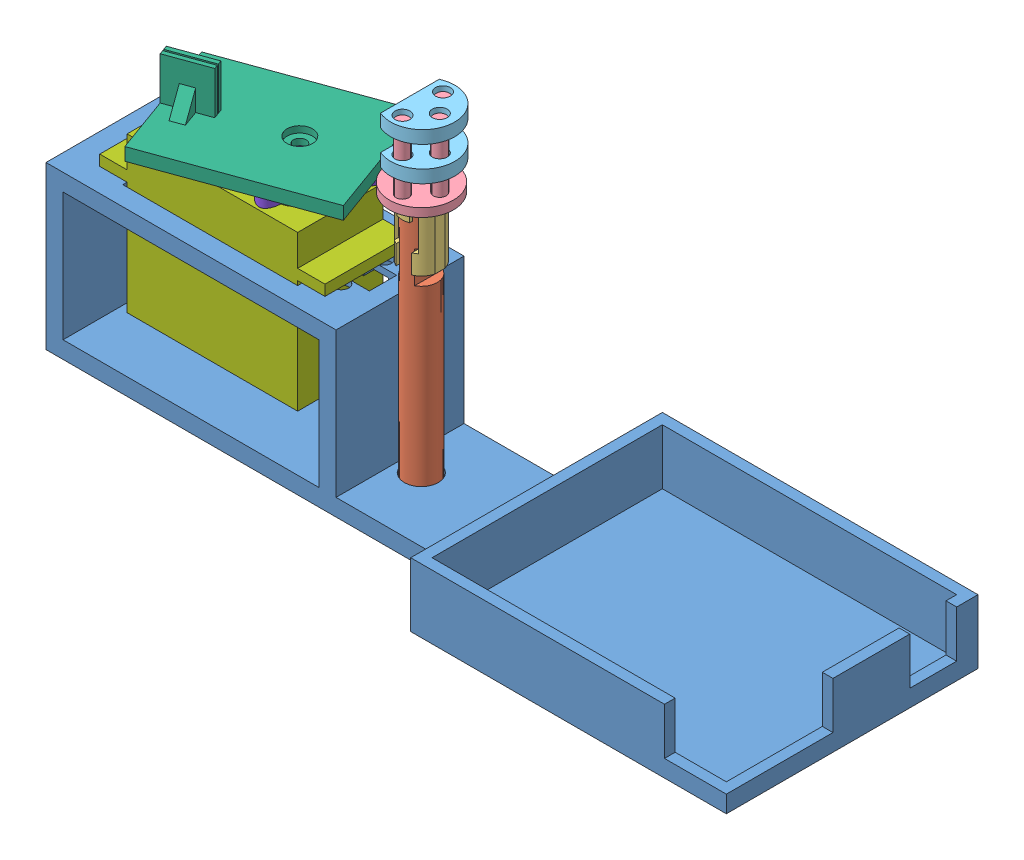
SolidWorks assembly Assembly, configuration Default. Lengths in mm.
Overall size (174 79 59).
9 component instances, 8 part files, 25 mates.
Components (placement in the parent):
- Banc de test-1: Banc de test [Default] at (112.6142 56.3386 131.8223) size (174 38 59)
- Pililer-1: Pililer [Default] at (48.6142 56.3386 131.8223) x (0.004917 0 -0.999988) z (0.999988 0 0.004917) size (24.5 59.5 24.5)
- Clips-1: Clips [Default] at (48.5148 115.8386 131.7007) x (0.004917 0 -0.999988) z (0.999988 0 0.004917) size (9 14 9)
- Support pinces-1: Support pinces [Default] at (48.5148 117.3386 131.7007) size (15 17 15)
- Shift-1: Shift [Default] at (48.8089 124.3386 131.7007) size (10.5 3 15)
- Shift-2: Shift [Default] at (48.8089 132.3386 131.7007) size (10.5 3 15)
- Extension servo-1: Extension servo [Default] at (19.6142 110.9386 131.3223) x (0.940197 0 -0.340632) z (0.340632 0 0.940197) size (40 13 30)
- Servomoteur-1: Servomoteur [Default] at (9.1142 67.8386 131.3223) x (-1 0 0) z (0 0 -1) size (52.8 37.6 20)
- Hélice servomoteur-1: Hélice servomoteur [Default] at (19.6142 105.4386 131.3223) x (0.940197 0 -0.340632) z (0.340632 0 0.940197) size (30 5.5 30)
Mates (geometry in assembly coordinates):
- Concentric1: concentric anti-aligned: cylinder of Banc de test v2-1 through (48.6142 50.3386 131.8223) axis (0 1 0) radius 4; cylinder of Pililer-1 through (48.6142 115.8386 131.8223) axis (0 -1 0) radius 3.75
- Coincident2: coincident aligned: plane of Banc de test v2-1 through (112.6142 56.3386 131.8223) normal (0 -1 0); plane of Pililer-1 through (48.6142 56.3386 131.8223) normal (0 -1 0)
- Lock1: lock: unknown of Banc de test v2-1; unknown of Pililer-1
- Coincident3: coincident anti-aligned: plane of Pililer-1 through (50.3642 56.3386 131.8309) normal (0.999988 0 0.004917); plane of Clips-1 through (50.3648 103.3386 131.7098) normal (-0.999988 0 -0.004917)
- Coincident4: coincident anti-aligned: plane of Pililer-1 through (48.6142 115.8386 131.8223) normal (0 1 0); plane of Clips-1 through (48.5148 115.8386 131.7007) normal (0 -1 0)
- Coincident5: coincident: cylinder of Pililer-1 through (48.6142 115.8386 131.8223) axis (0 -1 0) radius 3.75; line of Clips-1 through (49.9971 113.8386 135.308) axis (0 1 0)
- Coincident6: coincident anti-aligned: plane of Clips-1 through (48.5148 117.3386 131.7007) normal (0 1 0); plane of Support pinces-1 through (48.5148 117.3386 131.7007) normal (0 -1 0)
- Concentric3: concentric aligned: cylinder of Clips-1 through (48.5148 117.3386 131.7007) axis (0 -1 0) radius 4.5; cylinder of Support pinces-1 through (48.5148 119.3386 131.7007) axis (0 -1 0) radius 7.5
- Parallel1: parallel aligned: plane of Support pinces-1 through (48.5148 117.3386 131.7007) normal (0 0 1)
- Concentric4: concentric aligned: cylinder of Support pinces-1 through (48.8089 134.3386 126.9507) axis (0 -1 0) radius 1.5; cylinder of Shift-1 through (48.8089 127.3386 126.9507) axis (0 -1 0) radius 1.75
- Concentric5: concentric aligned: cylinder of Support pinces-1 through (48.8089 134.3386 136.4507) axis (0 -1 0) radius 1.5; cylinder of Shift-1 through (48.8089 127.3386 136.4507) axis (0 -1 0) radius 1.75
- Distance1: distance = 5 mm anti-aligned: plane of Shift-1 through (48.8089 124.3386 131.7007) normal (0 -1 0); plane of Support pinces-1 through (48.5148 119.3386 131.7007) normal (0 1 0)
- Concentric6: concentric aligned: cylinder of Support pinces-1 through (48.8089 134.3386 126.9507) axis (0 -1 0) radius 1.5; cylinder of Shift-2 through (48.8089 135.3386 126.9507) axis (0 -1 0) radius 1.75
- Concentric7: concentric aligned: cylinder of Support pinces-1 through (48.8089 134.3386 136.4507) axis (0 -1 0) radius 1.5; cylinder of Shift-2 through (48.8089 135.3386 136.4507) axis (0 -1 0) radius 1.75
- Distance2: distance = 5 mm anti-aligned: plane of Shift-2 through (48.8089 132.3386 131.7007) normal (0 -1 0); plane of Shift-1 through (48.8089 127.3386 131.7007) normal (0 1 0)
- Parallel2: parallel anti-aligned: plane of Banc de test v2-1 through (-24.3858 60.3386 116.8223) normal (0 1 0); plane of Servomoteur-1 through (9.1142 67.8386 131.3223) normal (0 -1 0)
- Parallel3: parallel anti-aligned: plane of Banc de test v2-1 through (39.6142 90.3386 116.8223) normal (-1 0 0); plane of Servomoteur-1 through (29.1142 94.3386 121.3223) normal (1 0 0)
- Coincident9: coincident anti-aligned: plane of Banc de test v2-1 through (112.6142 94.3386 131.8223) normal (0 1 0); plane of Servomoteur-1 through (9.1142 94.3386 131.3223) normal (0 -1 0)
- Coincident10: coincident anti-aligned: plane of Banc de test v2-1 through (-10.8858 94.3386 121.3223) normal (0 0 1); plane of Servomoteur-1 through (29.1142 94.3386 121.3223) normal (0 0 -1)
- Coincident11: coincident anti-aligned: plane of Banc de test v2-1 through (-10.8858 94.3386 121.3223) normal (1 0 0); plane of Servomoteur-1 through (-10.8858 94.3386 121.3223) normal (-1 0 0)
- Coincident12: coincident anti-aligned: plane of Servomoteur-1 through (19.6142 105.4386 131.3223) normal (0 1 0); plane of Hélice servomoteur-1 through (19.6142 105.4386 131.3223) normal (0 -1 0)
- Concentric8: concentric aligned: cylinder of Servomoteur-1 through (19.6142 105.4386 131.3223) axis (0 -1 0) radius 6.5; cylinder of Hélice servomoteur-1 through (19.6142 108.9386 131.3223) axis (0 -1 0) radius 4.5
- Coincident13: coincident anti-aligned: plane of Extension servo-1 through (19.6142 110.9386 131.3223) normal (0 -1 0); plane of Hélice servomoteur-1 through (19.6142 110.9386 131.3223) normal (0 1 0)
- Coincident14: coincident: plane of Extension servo-1 through (19.6142 110.9386 131.3223) normal (0.340632 0 0.940197); line of Hélice servomoteur-1 through (33.7171 110.9386 126.2129) axis (-0.940197 0 0.340632)
- Coincident15: coincident: plane of Extension servo-1 through (28.6077 113.9386 112.1099) normal (0.940197 0 -0.340632); point of Hélice servomoteur-1
